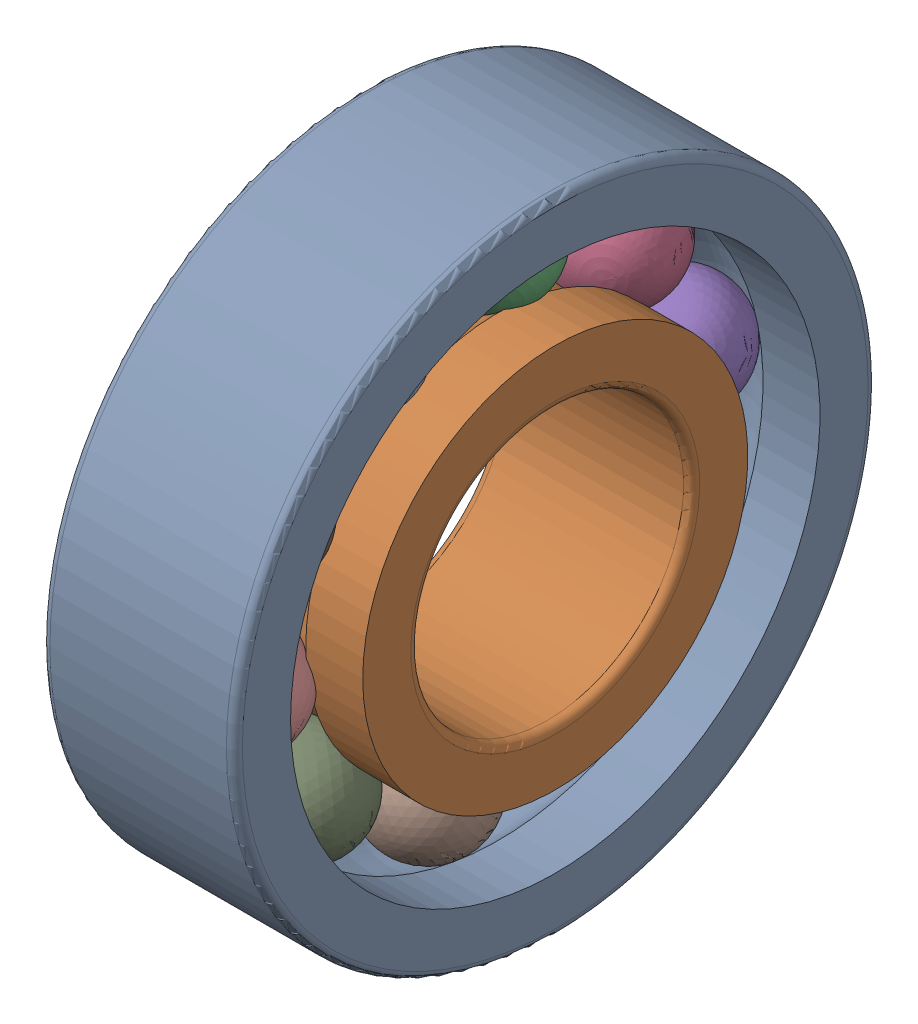
SolidWorks assembly Assem1, configuration Default. Lengths in mm.
Overall size (12 40 40).
12 component instances, 3 part files, 3 mates.
Components (placement in the parent):
- outer ring-1: outer ring [Default] at (-8.7077 15.3982 0.9179) size (12 40 40)
- innaer ring-1: innaer ring [Default] at (-8.299 1.3982 0.9179) x (1 0 0) z (0 0.557929 -0.829889) size (12 24 24)
- ball-1: ball [Default] at (-6.928 17.9713 -4.8572) x (0.771848 0.569842 -0.282011) z (-0.24175 0.673263 0.698766) size (7 7 7)
- ball-2: ball [Default] at (-6.928 11.4116 -13.4957) x (0.771848 0.29525 -0.563097) z (-0.24175 0.955406 0.16958) size (7 7 7)
- ball-3: ball [Default] at (-6.928 1.0271 -16.6287) x (0.771848 -0.092117 -0.629098) z (-0.24175 0.872616 -0.42438) size (7 7 7)
- ball-4: ball [Default] at (-6.928 -9.2156 -13.0594) x (0.771848 -0.444299 -0.454806) z (-0.24175 0.456517 -0.856242) size (7 7 7)
- ball-5: ball [Default] at (-6.928 -15.4043 -4.1514) x (0.771848 -0.626774 -0.106793) z (-0.24175 -0.133956 -0.961048) size (7 7 7)
- ball-6: ball [Default] at (-6.928 -15.1749 6.693) x (0.771848 -0.569842 0.282011) z (-0.24175 -0.673263 -0.698766) size (7 7 7)
- ball-7: ball [Default] at (-6.928 -8.6152 15.3315) x (0.771848 -0.29525 0.563097) z (-0.24175 -0.955406 -0.16958) size (7 7 7)
- ball-8: ball [Default] at (-6.928 1.7692 18.4645) x (0.771848 0.092117 0.629098) z (-0.24175 -0.872616 0.42438) size (7 7 7)
- ball-9: ball [Default] at (-6.928 12.012 14.8953) x (0.771848 0.444299 0.454806) z (-0.24175 -0.456517 0.856242) size (7 7 7)
- ball-10: ball [Default] at (-6.928 18.2006 5.9872) x (0.771848 0.626774 0.106793) z (-0.24175 0.133956 0.961048) size (7 7 7)
Mates (geometry in assembly coordinates):
- Concentric1: concentric aligned: circle of outer ring-1; circle of innaer ring-1
- Tangent4: tangent anti-aligned: torus of outer ring-1; sphere of ball-1
- Coincident2: coincident aligned: plane of outer ring-1 through (-9.5396 17.8982 0.9179) normal (-1 0 0); plane of innaer ring-1 through (-9.5396 -8.5605 -5.7772) normal (-1 0 0)
